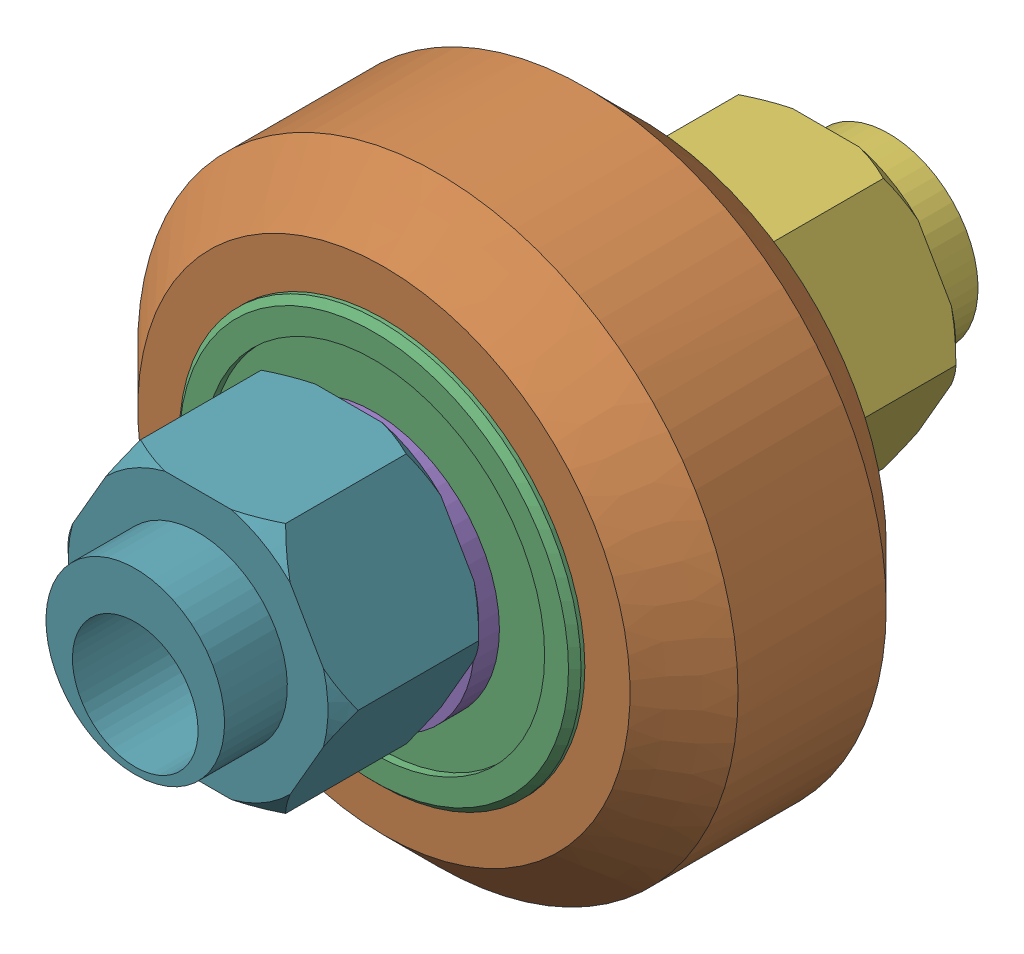
SolidWorks assembly Outboard Wheel Stack, configuration Default. Lengths in mm.
Overall size (23.9 23.9 30).
9 component instances, 4 part files, 0 mates.
Components (placement in the parent):
- Xtreme Solid V Wheel Kit Assembly_4-1: Xtreme Solid V Wheel Kit Assembly_4 [Default] at origin size (23.9 23.9 13)
  - Precision Shim - 10x5x1mm-1: Precision Shim - 10x5x1mm [Default] at origin size (10 10 1)
  - Xtreme Solid V Wheel Assembly_4-1: Xtreme Solid V Wheel Assembly_4 [Default] at (84.85 25.79 -23.5) size (23.9 23.9 11)
    - Xtreme Solid V Wheel-1: Xtreme Solid V Wheel [Default] at (-84.85 -25.79 30) x (0 0 1) z (-1 0 0) size (10.2 23.9 23.9)
    - Wheel+Kit+-+5x16x5mm+Sealed+Radial+Ball+Bearing.step.f3d-1: Wheel+Kit+-+5x16x5mm+Sealed+Radial+Ball+Bearing.step.f3d [Default] at (-84.85 -25.79 30) x (0 1 0) z (-1 0 0) size (16 5 16)
    - Wheel+Kit+-+5x16x5mm+Sealed+Radial+Ball+Bearing.step.f3d-2: Wheel+Kit+-+5x16x5mm+Sealed+Radial+Ball+Bearing.step.f3d [Default] at (-84.85 -25.79 30) x (0 1 0) z (1 0 0) size (16 5 16)
  - Precision Shim - 10x5x1mm-2: Precision Shim - 10x5x1mm [Default] at (0 0 12) size (10 10 1)
- Eccentric Spacer 6mm-1: Eccentric Spacer 6mm [Default] at (0 0.79 -6) x (1 0 0) z (0 -1 0) size (11.55 8.5 10)
- Eccentric Spacer 6mm-2: Eccentric Spacer 6mm [Default] at (0 0.79 19) x (-1 0 0) z (0 -1 0) size (11.55 8.5 10)
